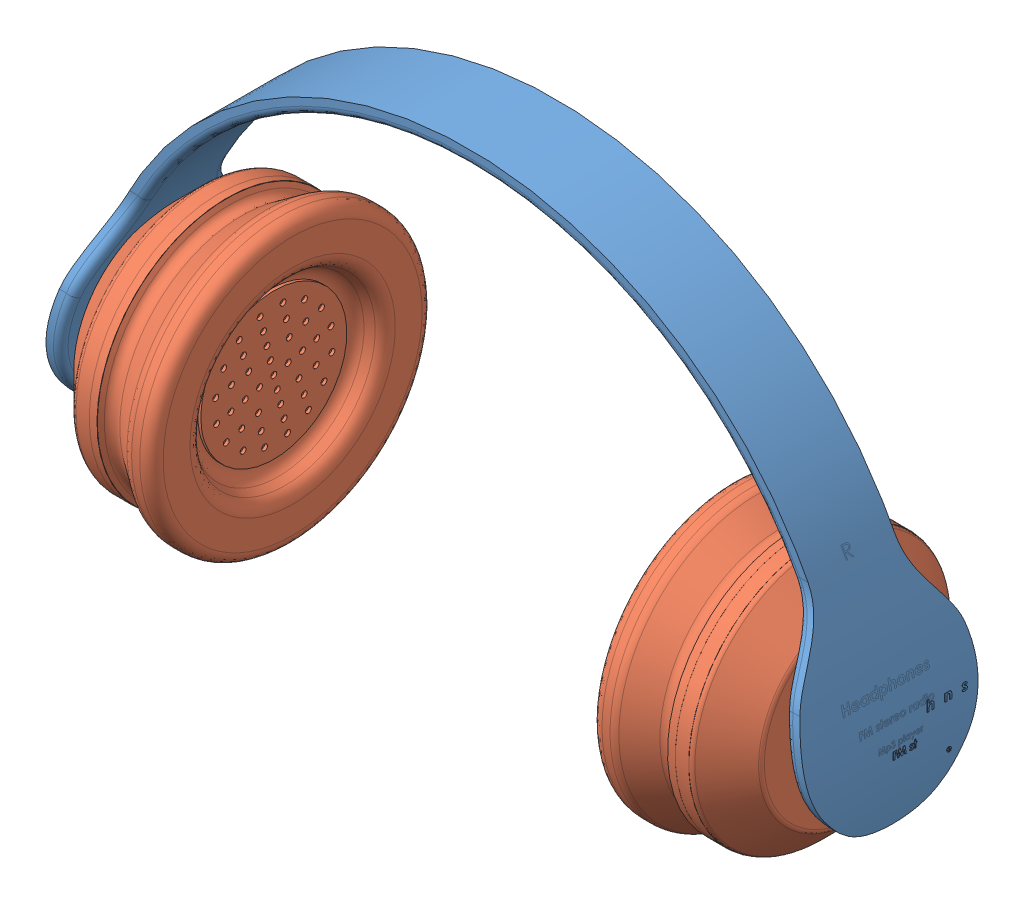
SolidWorks assembly Assem1, configuration Default. Lengths in mm.
Overall size (261.33 173.33 117.71).
3 component instances, 2 part files, 6 mates.
Components (placement in the parent):
- Headphone-TOP-2: Headphone-TOP [Default] at (111.2376 130.8495 137.842) size (270.76 144.49 65.4)
- Earphone-3: Earphone [Default] at (237.2376 146.3752 167.842) x (0 -0.965391 0.260806) z (0 -0.260806 -0.965391) size (96 51.41 96)
- Earphone-4: Earphone [Default] at (-14.7624 146.3752 167.842) x (0 -0.972424 -0.233221) z (0 -0.233221 0.972424) size (96 51.41 96)
Mates (geometry in assembly coordinates):
- Coincident1: coincident: line of Headphone-TOP-2 through (229.1928 146.3752 167.842) axis (1 0 0); line of Earphone-3 through (211.768 146.3752 167.842) axis (1 0 0)
- Tangent2: tangent: cylinder of Headphone-TOP-2 through (111.2376 130.8495 200.4453) axis (0 0 -1) radius 126; plane of Earphone-3 through (237.2376 160.8561 163.9299) normal (1 0 0)
- Lock1: lock: unknown of Headphone-TOP-2; unknown of Earphone-3
- Coincident2: coincident: line of Headphone-TOP-2 through (-14.7624 146.3752 167.842) axis (1 0 0); line of Earphone-4 through (10.7072 146.3752 167.842) axis (-1 0 0)
- Tangent4: tangent: cylinder of Headphone-TOP-2 through (111.2376 130.8495 200.4453) axis (0 0 -1) radius 126; plane of Earphone-4 through (-14.7624 160.9615 171.3403) normal (-1 0 0)
- Lock2: lock: unknown of Headphone-TOP-2; unknown of Earphone-4
